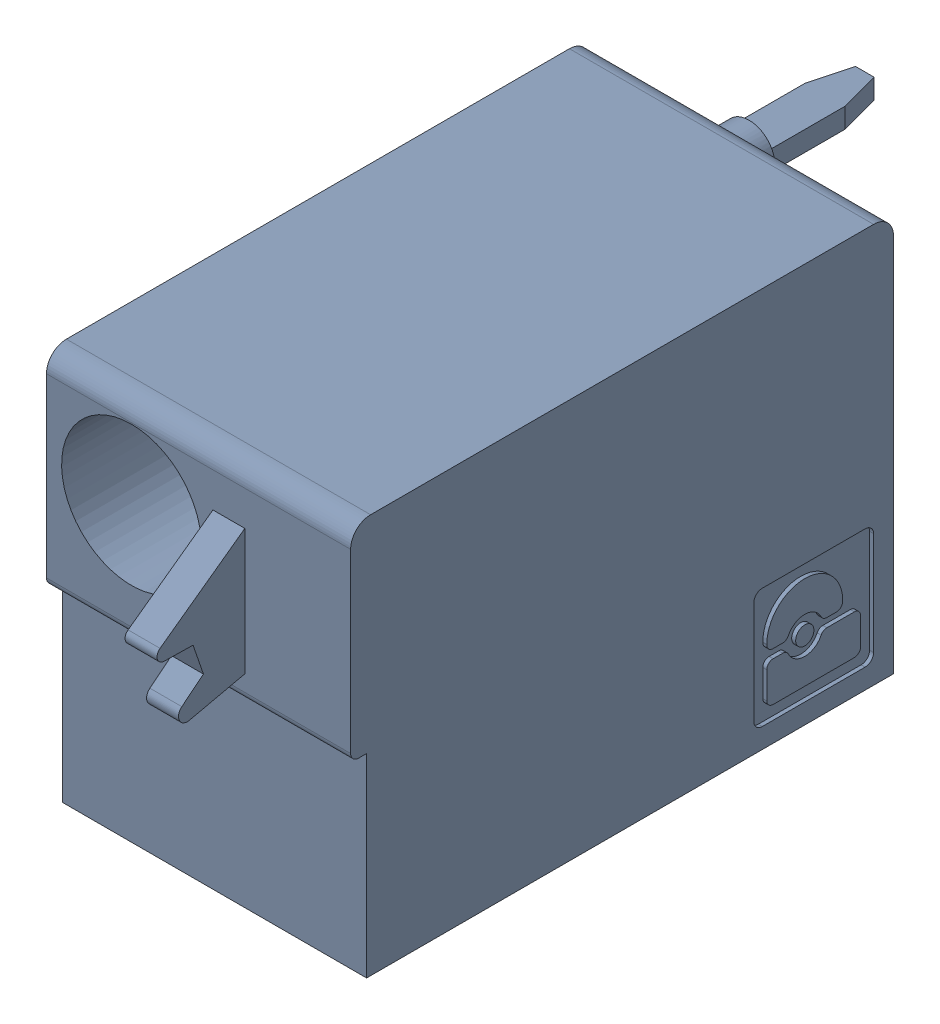
SolidWorks assembly J4, configuration Default. Lengths in mm.
Overall size (7.62 10 19.2).
2 component instances, 1 part files, 0 mates.
Components (placement in the parent):
- 1790487-1: 1790487 [Default] at (-2.135 -5.67 -10.6) x (0 1 0) z (1 0 0) size (10 19.2 7.62)
  - ffkdsa1-v2-7.62-1: ffkdsa1-v2-7.62 [Default] at (-15.6914 -27.508 9.12) x (0 -1 0) z (0 0 1) size (19.2 10 7.62)
